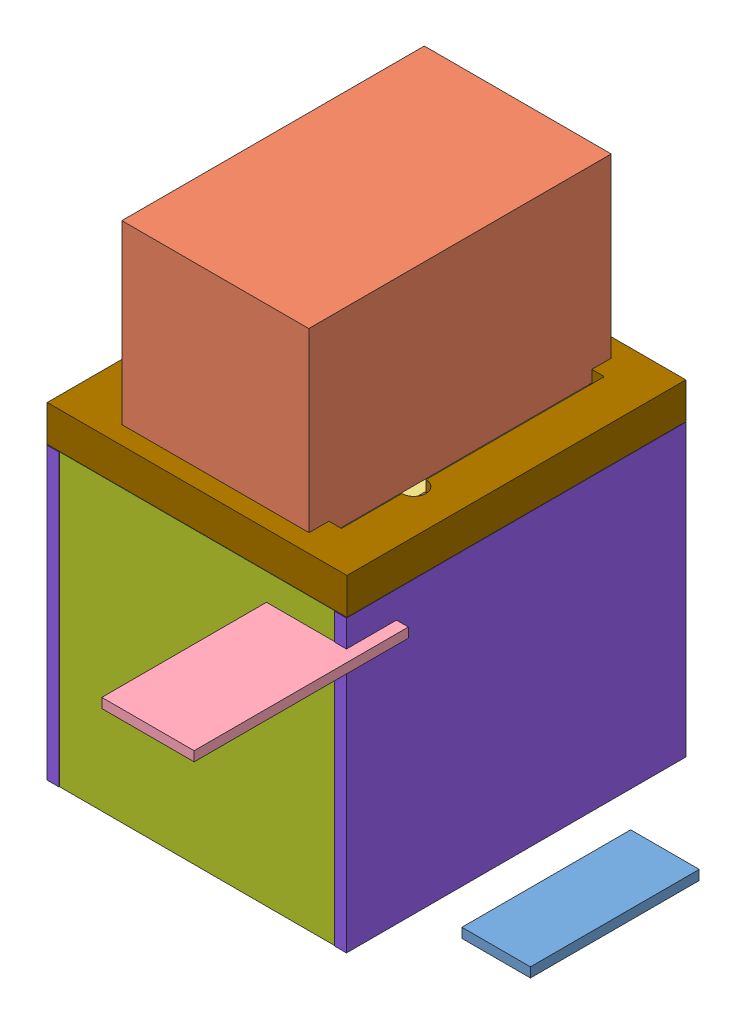
SolidWorks assembly LightBaseAsm, configuration Default. Lengths in mm.
Overall size (144.36 132.2 132.3).
11 component instances, 9 part files, 23 mates.
Components (placement in the parent):
- Arduino-1: Arduino [Default] at (4.0851 22.0382 57.9317) size (18.01 2.54 44.35)
- Elephant-1: Elephant [Default] at (-107.4516 68.922 35.7298) size (49.11 49.56 79.46)
- LEDBoard-1: LEDBoard [Default] at (-109.6932 65.747 30.453) size (53.59 2.54 68.91)
- PowerBoard-1: PowerBoard [Default] at (-64.6622 52.8911 83.7805) size (24.26 2.54 56.27)
- BatteryBank-1: BatteryBank [Default] at (-115.5352 -7.3725 33.5899) size (65.28 22.99 75.18)
- BatteryBankHolder-1: BatteryBankHolder [Default] at (-119.0912 -0.3875 37.3364) size (72.39 3.17 82.68)
- FrontBackPanel-1: FrontBackPanel [Default] at (-119.0912 -13.7225 -48.5156) size (72.39 76.2 3.17)
- FrontBackPanel-2: FrontBackPanel [Default] at (-119.0912 -13.7225 37.3364) size (72.39 76.2 3.17)
- LeftRightPanel-1: LeftRightPanel [Default] at (-122.2662 -13.7225 40.6384) size (3.17 76.2 89.15)
- LeftRightPanel-2: LeftRightPanel [Default] at (-46.7012 -13.7225 40.6384) size (3.17 76.2 89.15)
- TopCap-1: TopCap [Default] at (-118.9642 59.397 -45.2771) x (0 0 1) z (-1 0 0) size (89.03 12.7 78.74)
Mates (geometry in assembly coordinates):
- Distance1: distance = 6.985 mm: plane of BatteryBankHolder-1 through (-119.0912 -0.3875 37.3364) normal (0 1 0); plane of BatteryBank-1 through (-115.5352 -7.3725 33.5899) normal (0 1 0)
- Width1: width: plane of BatteryBankHolder-1 through (-116.5512 2.7875 -45.3406) normal (0 0 -1); plane of BatteryBankHolder-1 through (-116.5512 2.7875 37.3364) normal (0 0 1); plane of BatteryBank-1 through (-115.5352 12.3125 -41.5941) normal (0 0 -1); plane of BatteryBank-1 through (-115.5352 12.3125 33.5899) normal (0 0 1)
- Width2: width: plane of BatteryBankHolder-1 through (-46.7012 2.7875 34.7964) normal (1 0 0); plane of BatteryBankHolder-1 through (-119.0912 2.7875 34.7964) normal (-1 0 0); plane of BatteryBank-1 through (-115.5352 12.3125 33.5899) normal (-1 0 0); plane of BatteryBank-1 through (-50.2572 12.3125 33.5899) normal (1 0 0)
- Coincident2: coincident: plane of FrontBackPanel-1 through (-119.0912 -13.7225 -45.3406) normal (0 -1 0); plane of FrontBackPanel-2 through (-119.0912 -13.7225 40.5114) normal (0 -1 0)
- Coincident3: coincident: plane of FrontBackPanel-1 through (-119.0912 -13.7225 -45.3406) normal (0 -1 0); plane of LeftRightPanel-1 through (-119.0912 -13.7225 40.6384) normal (0 -1 0)
- Coincident4: coincident: plane of LeftRightPanel-1 through (-119.0912 -13.7225 40.6384) normal (0 -1 0); plane of LeftRightPanel-2 through (-43.5262 -13.7225 40.6384) normal (0 -1 0)
- Distance2: distance = 6.35 mm: plane of LeftRightPanel-2 through (-43.5262 -13.7225 40.6384) normal (0 -1 0); plane of BatteryBank-1 through (-115.5352 -7.3725 33.5899) normal (0 -1 0)
- Coincident6: coincident: plane of BatteryBankHolder-1 through (-46.7012 2.7875 34.7964) normal (1 0 0); plane of LeftRightPanel-2 through (-46.7012 -13.7225 40.6384) normal (-1 0 0)
- Coincident7: coincident: plane of BatteryBankHolder-1 through (-119.0912 2.7875 34.7964) normal (-1 0 0); plane of LeftRightPanel-1 through (-119.0912 -13.7225 40.6384) normal (1 0 0)
- Coincident8: coincident: plane of BatteryBankHolder-1 through (-116.5512 2.7875 -45.3406) normal (0 0 -1); plane of FrontBackPanel-1 through (-119.0912 -13.7225 -45.3406) normal (0 0 1)
- Coincident9: coincident: plane of BatteryBankHolder-1 through (-116.5512 2.7875 37.3364) normal (0 0 1); plane of FrontBackPanel-2 through (-119.0912 -13.7225 37.3364) normal (0 0 -1)
- Coincident10: coincident: plane of FrontBackPanel-1 through (-46.7012 -13.7225 -45.3406) normal (1 0 0); plane of LeftRightPanel-2 through (-46.7012 -13.7225 40.6384) normal (-1 0 0)
- Coincident11: coincident: plane of FrontBackPanel-2 through (-119.0912 -13.7225 40.5114) normal (-1 0 0); plane of LeftRightPanel-1 through (-119.0912 -13.7225 40.6384) normal (1 0 0)
- Coincident12: coincident: plane of FrontBackPanel-1 through (-119.0912 -13.7225 -48.5156) normal (0 0 -1); plane of LeftRightPanel-2 through (-43.5262 -13.7225 -48.5156) normal (0 0 -1)
- Coincident13: coincident: plane of FrontBackPanel-1 through (-119.0912 -13.7225 -48.5156) normal (0 0 -1); plane of LeftRightPanel-1 through (-119.0912 -13.7225 -48.5156) normal (0 0 -1)
- Width3: width: plane of TopCap-1 through (-43.5262 68.922 40.5114) normal (1 0 0); plane of TopCap-1 through (-122.2662 68.922 40.5114) normal (-1 0 0); plane of LeftRightPanel-1 through (-122.2662 -13.7225 40.6384) normal (-1 0 0); plane of LeftRightPanel-2 through (-43.5262 -13.7225 40.6384) normal (1 0 0)
- Width4: width: plane of TopCap-1 through (-43.5262 68.922 -48.5156) normal (0 0 -1); plane of TopCap-1 through (-43.5262 68.922 40.5114) normal (0 0 1); plane of FrontBackPanel-1 through (-119.0912 -13.7225 -48.5156) normal (0 0 -1); plane of FrontBackPanel-2 through (-119.0912 -13.7225 40.5114) normal (0 0 1)
- Width5: width: plane of LEDBoard-1 through (-109.6932 68.287 30.453) normal (-1 0 0); plane of LEDBoard-1 through (-56.0992 68.287 30.453) normal (1 0 0); plane of TopCap-1 through (-54.9562 65.747 -38.5461) normal (-1 0 0); plane of TopCap-1 through (-110.8362 65.747 -38.5461) normal (1 0 0)
- Width6: width: plane of LEDBoard-1 through (-109.6932 68.287 30.453) normal (0 0 1); plane of LEDBoard-1 through (-109.6932 68.287 -38.4572) normal (0 0 -1); plane of TopCap-1 through (-110.8362 65.747 -38.5461) normal (0 0 1); plane of TopCap-1 through (-110.8362 65.747 30.5419) normal (0 0 -1)
- Coincident15: coincident: plane of LEDBoard-1 through (-109.6932 65.747 30.453) normal (0 -1 0); plane of TopCap-1 through (-54.9562 65.747 11.4919) normal (0 1 0)
- Width7: width: plane of Elephant-1 through (-107.4516 118.4774 35.7298) normal (-1 0 0); plane of Elephant-1 through (-58.3407 118.4774 35.7298) normal (1 0 0); plane of TopCap-1 through (-54.9562 65.747 -38.5461) normal (-1 0 0); plane of TopCap-1 through (-110.8362 65.747 -38.5461) normal (1 0 0)
- Width8: width: plane of Elephant-1 through (-107.4516 118.4774 -43.7341) normal (0 0 -1); plane of Elephant-1 through (-107.4516 118.4774 35.7298) normal (0 0 1); plane of TopCap-1 through (-118.9642 72.097 -43.7531) normal (0 0 1); plane of TopCap-1 through (-118.9642 72.097 35.7489) normal (0 0 -1)
- Coincident16: coincident: plane of Elephant-1 through (-107.4516 68.922 35.7298) normal (0 -1 0); plane of TopCap-1 through (-118.9642 68.922 -45.2771) normal (0 1 0)
